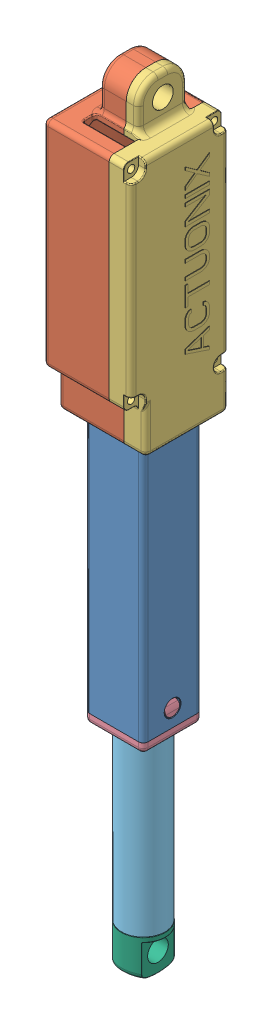
SolidWorks assembly LA1, configuration Default. Lengths in mm.
6 component instances, 6 part files, 12 mates.
Components (placement in the parent):
- EXTENSION_10404_50MM-1: EXTENSION_10404_50MM [Default] at (14.0586 27.9726 -26.8474) size (12 60 12)
- CLAMSHELL_BOT_10654-1: CLAMSHELL_BOT_10654 [Default] at (14.0586 74.3726 -35.3474) x (0 0 -1) z (0 -1 0) size (20 14.51 62.21)
- CLAMSHELL_TOP_10653-1: CLAMSHELL_TOP_10653 [Default] at (14.0586 74.3726 -35.3474) x (0 0 -1) z (0 -1 0) size (20.21 11.32 62)
- GUIDE_10429-1: GUIDE_10429 [Default] at (14.0586 -34.0274 -26.8474) x (0 0 -1) z (-1 0 0) size (12 7.21 12)
- SHAFT_10409_50MM2-1: SHAFT_10409_50MM2 [Default] at (14.0586 -11.0415 -26.8474) size (8.95 58 8.95)
- PLUG_10428-1: PLUG_10428 [Default] at (14.0586 -76.0415 -26.8474) x (1 0 0) z (0 0 -1) size (9 14 9.15)
Mates (geometry in assembly coordinates):
- Concentric1: concentric aligned: cone of GUIDE_10429-1 through (14.0586 -27.0274 -26.8474) axis (0 -1 0); cylinder of SHAFT_10409_50MM2-1 through (14.0586 -11.0415 -26.8474) axis (0 -1 0) radius 4.475
- Coincident2: coincident aligned: plane of EXTENSION_10404_50MM-1 through (20.0586 27.9726 -32.8474) normal (1 0 0); plane of GUIDE_10429-1 through (20.0586 -34.0274 -20.8474) normal (1 0 0)
- Coincident3: coincident aligned: plane of EXTENSION_10404_50MM-1 through (20.0586 27.9726 -20.8474) normal (0 0 1); plane of GUIDE_10429-1 through (8.0586 -34.0274 -20.8474) normal (0 0 1)
- Coincident4: coincident anti-aligned: plane of EXTENSION_10404_50MM-1 through (14.0586 -32.0274 -26.8474) normal (0 -1 0); plane of GUIDE_10429-1 through (14.0586 -32.0274 -26.8474) normal (0 1 0)
- Coincident6: coincident anti-aligned: plane of CLAMSHELL_BOT_10654-1 through (18.5586 74.3726 -35.3474) normal (1 0 0); plane of CLAMSHELL_TOP_10653-1 through (18.5586 70.3726 -18.8474) normal (-1 0 0)
- Concentric2: concentric aligned: cylinder of CLAMSHELL_BOT_10654-1 through (4.9547 22.3726 -34.3474) axis (1 0 0) radius 1; cylinder of CLAMSHELL_TOP_10653-1 through (4.9547 22.3726 -34.3474) axis (1 0 0) radius 1
- Coincident7: coincident anti-aligned: plane of EXTENSION_10404_50MM-1 through (20.0586 27.9726 -32.8474) normal (1 0 0); plane of CLAMSHELL_TOP_10653-1 through (20.0586 21.3726 -32.8474) normal (-1 0 0)
- Concentric3: concentric anti-aligned: cylinder of EXTENSION_10404_50MM-1 through (24.0586 24.4726 -26.8474) axis (-1 0 0) radius 1.625; cylinder of CLAMSHELL_TOP_10653-1 through (20.0586 24.4726 -26.8474) axis (1 0 0) radius 1.5
- Concentric4: concentric anti-aligned: cylinder of SHAFT_10409_50MM2-1 through (14.0586 -11.0415 -26.8474) axis (0 -1 0) radius 3.5; cylinder of PLUG_10428-1 through (14.0586 -69.3415 -26.8474) axis (0 1 0) radius 4
- Coincident8: coincident anti-aligned: plane of SHAFT_10409_50MM2-1 through (14.0586 -69.0415 -26.8474) normal (0 -1 0); plane of PLUG_10428-1 through (14.0586 -69.0415 -26.8474) normal (0 1 0)
- Coincident9: coincident aligned: plane of CLAMSHELL_BOT_10654-1 through (5.0586 74.3726 -35.3474) normal (0 0 -1); plane of CLAMSHELL_TOP_10653-1 through (5.0586 74.3726 -35.3474) normal (0 0 -1)
- Parallel1: parallel aligned: plane of EXTENSION_10404_50MM-1 through (8.0586 27.9726 -32.8474) normal (0 0 -1); plane of CLAMSHELL_BOT_10654-1 through (5.0586 74.3726 -35.3474) normal (0 0 -1)
